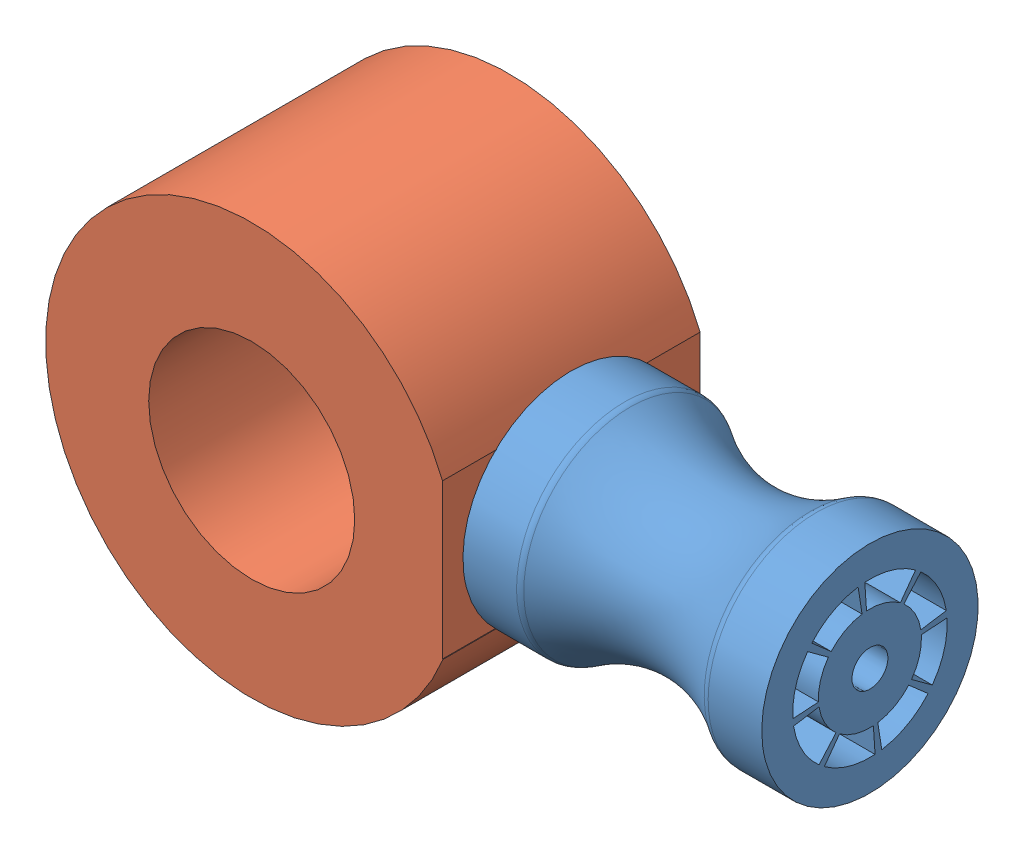
SolidWorks assembly Boom-mast-coupling-assembly, configuration Défaut. Lengths in mm.
Overall size (135 80 50).
2 component instances, 2 part files, 2 mates.
Components (placement in the parent):
- rubber-mast-joint-1: rubber-mast-joint [Défaut] at (-7.5069 16.1703 10.5) x (0 -0.188932 0.98199) z (-1 0 0) size (42 42 58)
- Boom-mast-coupling-1: Boom-mast-coupling [Défaut] at (-102.5069 16.1249 -14.5) size (77.12 80 50)
Mates (geometry in assembly coordinates):
- Coïncidente1: coincident anti-aligned: plane of rubber-mast-joint-1 through (-65.5069 16.1703 10.5) normal (-1 0 0); plane of Boom-mast-coupling-1 through (-65.5069 31.2157 -14.5) normal (1 0 0)
- Coaxiale1: concentric anti-aligned: cylinder of rubber-mast-joint-1 through (-65.5069 16.1703 10.5) axis (-1 0 0) radius 3.5; cylinder of Boom-mast-coupling-1 through (-65.5069 16.1703 10.5) axis (1 0 0) radius 3.4
